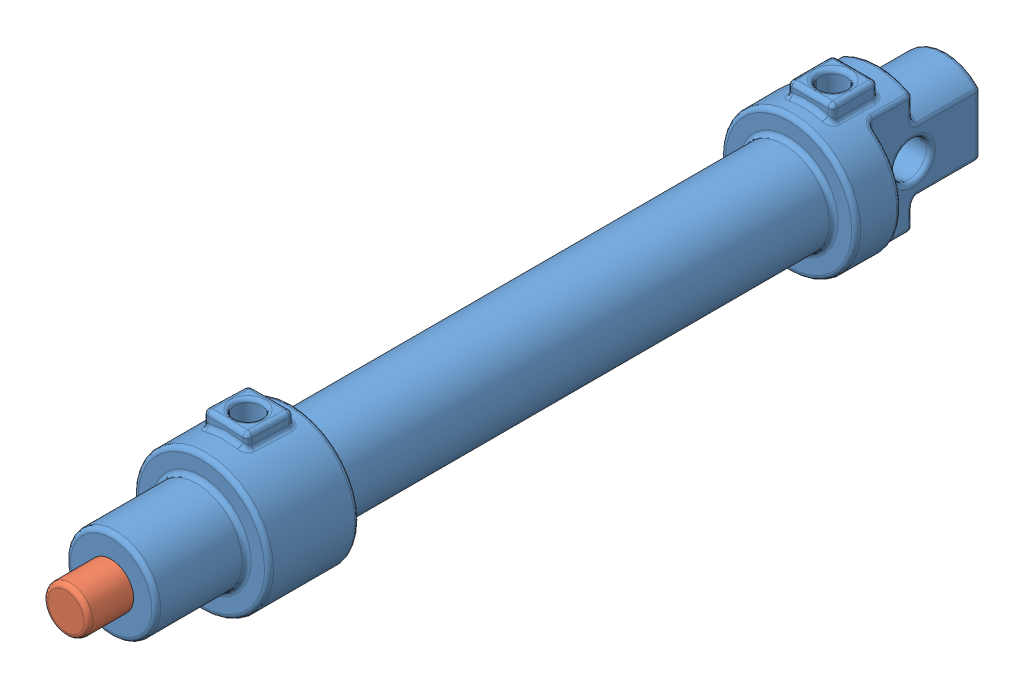
SolidWorks assembly cylinder assembly, configuration Default. Lengths in mm.
Overall size (30 32.55 195).
2 component instances, 2 part files, 2 mates.
Components (placement in the parent):
- cylinder-1: cylinder [Default] at (-92.1798 -0.5475 141.514) size (30 32.55 185)
- cylinder rod-1: cylinder rod [Default] at (-92.1798 -0.5475 51.514) x (0.995961 0.089791 0) z (0.089791 -0.995961 0) size (10 100 10)
Mates (geometry in assembly coordinates):
- Concentric1: concentric anti-aligned: cylinder of cylinder-1 through (-92.1798 -0.5475 -8.486) axis (0 0 1) radius 5; cylinder of cylinder rod-1 through (-92.1798 -0.5475 151.514) axis (0 0 -1) radius 5
- LimitDistance2: limit distance = 10 mm: plane of cylinder-1 through (-92.1798 -0.5475 141.514) normal (0 0 1); plane of cylinder rod-1 through (-92.1798 -0.5475 151.514) normal (0 0 1)
